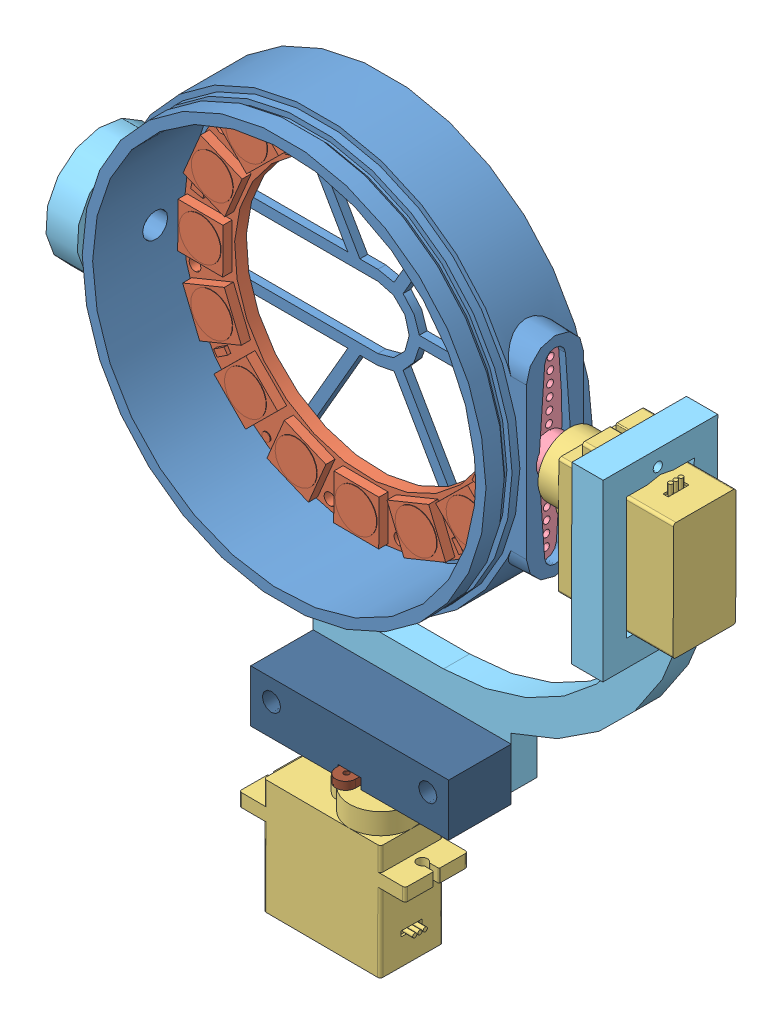
SolidWorks assembly assembly, configuration Default. Lengths in mm.
Overall size (116 139.39 23.52).
21 component instances, 11 part files, 28 mates.
Components (placement in the parent):
- ring-shell-1: ring-shell [Default] at (19.0926 43.4847 53.1336) size (80 79.5 19.5)
- NeoPixelRing16-d7-1: NeoPixelRing16-d7 [Default] at (19.0905 43.5003 55.614) x (-0.980853 -0.194751 0) z (0 0 1) size (70.4 70.4 4.08)
- servo-1: servo [Varsayılan] at (87.7926 38.2347 60.6442) x (0 0.002021 0.999998) z (0 -0.999998 0.002021) size (12 30 32)
- servo horn 2 v1-1: servo horn 2 v1 [Default] at (57.7926 43.4847 60.6336) x (0 -0.029252 -0.999572) z (0 0.999572 -0.029252) size (7.2 3.7 35.2)
- arm-1: arm [Default] at (25.2926 32.4615 49.1558) x (1 0 0) z (0 0.002021 0.999998) size (107 77.5 22)
- bearing 625-1: bearing 625 [Default] at (-27.2074 43.4837 60.1336) size (5 16 16)
  - SKF 625.STEP-1: SKF 625.STEP [Default] at origin size (5 16 16)
    - SKF 625 Inner Race^SKF 625.STEP-1: SKF 625 Inner Race^SKF 625.STEP [Default] at origin size (5 8.4 8.4)
    - SKF 625 Outer Race^SKF 625.STEP-1: SKF 625 Outer Race^SKF 625.STEP [Default] at origin size (5 16 16)
    - SKF 625 Ball^SKF 625.STEP-1: SKF 625 Ball^SKF 625.STEP [Default] at origin size (2.38 2.38 2.38)
    - SKF 625 Ball^SKF 625.STEP-2: SKF 625 Ball^SKF 625.STEP [Default] x (1 0 0) z (0 0.707107 0.707107) size (2.38 2.38 2.38)
    - SKF 625 Ball^SKF 625.STEP-3: SKF 625 Ball^SKF 625.STEP [Default] x (1 0 0) z (0 1 0) size (2.38 2.38 2.38)
    - SKF 625 Ball^SKF 625.STEP-4: SKF 625 Ball^SKF 625.STEP [Default] x (1 0 0) z (0 0.707107 -0.707107) size (2.38 2.38 2.38)
    - SKF 625 Ball^SKF 625.STEP-5: SKF 625 Ball^SKF 625.STEP [Default] x (1 0 0) z (0 0 -1) size (2.38 2.38 2.38)
    - SKF 625 Ball^SKF 625.STEP-6: SKF 625 Ball^SKF 625.STEP [Default] x (1 0 0) z (0 -0.707107 -0.707107) size (2.38 2.38 2.38)
    - SKF 625 Ball^SKF 625.STEP-7: SKF 625 Ball^SKF 625.STEP [Default] x (1 0 0) z (0 -1 0) size (2.38 2.38 2.38)
    - SKF 625 Ball^SKF 625.STEP-8: SKF 625 Ball^SKF 625.STEP [Default] x (1 0 0) z (0 -0.707107 0.707107) size (2.38 2.38 2.38)
    - SKF 625 Cage^SKF 625.STEP-1: SKF 625 Cage^SKF 625.STEP [Default] at (2.5 0 0) x (0 0 -1) z (1 0 0) size (12.17 12.17 2.88)
- sg90-adapter-1: sg90-adapter [Default] at (25.2926 -20.0283 54.2619) x (1 0 0) z (0 0.002021 0.999998) size (38 10 12)
- SG90 horn-cross-1: SG90 horn-cross [Varsayılan] at (25.2926 -24.5161 60.271) x (1 0 0) z (0 0.002021 0.999998) size (34.3 4 16.6)
- servo-2: servo [Varsayılan] at (20.0427 -54.5161 60.3072) x (-0.004653 0.002021 0.999987) z (-0.999989 -0.000009 -0.004653) size (12 30 32)
Mates (geometry in assembly coordinates):
- Coincident1: coincident anti-aligned: plane of ring-shell-1 through (19.0926 43.4847 54.6336) normal (0 0 1); plane of NeoPixelRing16-d7-1 through (19.0882 43.0207 54.6336) normal (0 0 -1)
- Concentric1: concentric anti-aligned: cylinder of ring-shell-1 through (19.0926 43.4847 66.1336) axis (0 0 -1) radius 36.75; circle of NeoPixelRing16-d7-1
- Coincident2: coincident anti-aligned: plane of ring-shell-1 through (56.5926 27.4847 60.6336) normal (1 0 0); plane of servo horn 2 v1-1 through (56.5926 36.4877 60.8383) normal (-1 0 0)
- Coincident4: coincident anti-aligned: plane of ring-shell-1 through (19.0926 43.4847 53.1336) normal (0 0 -1); plane of esp-case-1 through (19.3316 43.1534 53.1336) normal (0 0 1)
- Coincident5: coincident anti-aligned: plane of ring-shell-1 through (19.0926 43.4847 53.1336) normal (0 0 -1); plane of esp-case-2 through (19.0905 43.5003 53.1336) normal (0 0 1)
- Coincident6: coincident aligned: circle of ESP-wrover-B_board-1; circle of esp-case-2
- Coincident7: coincident aligned: circle of ESP-wrover-B_board-1; circle of esp-case-2
- Concentric5: concentric aligned: circle of servo-1; cylinder of servo horn 2 v1-1 through (57.7926 43.4847 60.6336) axis (-1 0 0) radius 2.5
- Concentric6: concentric aligned: circle of servo horn 2 v1-1; circle of ring-shell-1
- Parallel1: parallel anti-aligned: plane of ring-shell-1 through (-20.6584 59.6264 62.6286) normal (0 -0.07084 -0.997488); plane of servo horn 2 v1-1 through (57.7926 47.1563 63.0272) normal (0 0.07084 0.997488)
- Concentric7: concentric anti-aligned: circle of ring-shell-1; circle of esp-case-2
- Concentric8: concentric anti-aligned: circle of ring-shell-1; circle of esp-case-2
- Coincident10: coincident anti-aligned: plane of servo-1 through (72.7926 22.7459 66.1755) normal (1 0 0); plane of arm-1 through (72.7926 32.4615 49.1558) normal (-1 0 0)
- Coincident11: coincident anti-aligned: plane of servo-1 through (57.7926 43.4847 60.6336) normal (-1 0 0); plane of servo horn 2 v1-1 through (57.7926 43.4847 60.6336) normal (1 0 0)
- Concentric9: concentric aligned: cylinder of arm-1 through (-28.2074 43.4837 60.1336) axis (1 0 0) radius 8.35; cylinder of bearing 625-1/SKF 625.STEP-1/SKF 625 Outer Race^SKF 625.STEP-1 through (-22.5074 43.4837 60.1336) axis (1 0 0) radius 8
- Coincident12: coincident anti-aligned: plane of arm-1 through (-27.2074 43.4837 60.1336) normal (1 0 0); plane of bearing 625-1/SKF 625.STEP-1/SKF 625 Outer Race^SKF 625.STEP-1 through (-27.2074 51.1837 60.1336) normal (-1 0 0)
- Coincident13: coincident anti-aligned: plane of servo-1 through (86.7926 48.9968 66.6225) normal (0 0.002021 0.999998); plane of arm-1 through (78.7926 32.4969 66.6558) normal (0 -0.002021 -0.999998)
- Coincident14: coincident anti-aligned: plane of servo-1 through (86.7926 49.4736 55.1215) normal (0 0.999998 -0.002021); plane of arm-1 through (78.7926 49.4615 49.1215) normal (0 -0.999998 0.002021)
- Coincident15: coincident anti-aligned: circle of arm-1; circle of sg90-adapter-1
- Coincident16: coincident anti-aligned: plane of arm-1 through (25.2926 32.4716 54.1558) normal (0 0.002021 0.999998); plane of sg90-adapter-1 through (25.2926 -20.0283 54.2619) normal (0 -0.002021 -0.999998)
- Concentric10: concentric aligned: circle of arm-1; circle of sg90-adapter-1
- Concentric12: concentric aligned: circle of sg90-adapter-1; circle of servo horn 2 v1-2
- Parallel2: parallel aligned: plane of sg90-adapter-1 through (25.2926 -20.004 66.2619) normal (0 0.002021 0.999998); plane of servo horn 2 v1-2 through (28.383 -24.4815 56.5745) normal (0 -0.088913 0.996039)
- Concentric13: concentric anti-aligned: circle of sg90-adapter-1; circle of SG90 horn-cross-1
- Parallel4: parallel aligned: plane of sg90-adapter-1 through (6.2926 -15.004 66.2518) normal (-1 0 0); plane of SG90 horn-cross-1 through (23.3926 -23.0161 60.268) normal (-1 0 0)
- Coincident25: coincident anti-aligned: plane of sg90-adapter-1 through (8.3426 -23.0161 60.268) normal (0 -0.999998 0.002021); plane of SG90 horn-cross-1 through (25.2926 -23.0161 60.268) normal (0 0.999998 -0.002021)
- Concentric14: concentric anti-aligned: circle of SG90 horn-cross-1; circle of servo-2
- Coincident26: coincident anti-aligned: plane of SG90 horn-cross-1 through (25.2926 -24.5161 60.271) normal (0 -0.999998 0.002021); plane of servo-2 through (25.2926 -24.5161 60.271) normal (0 0.999998 -0.002021)
